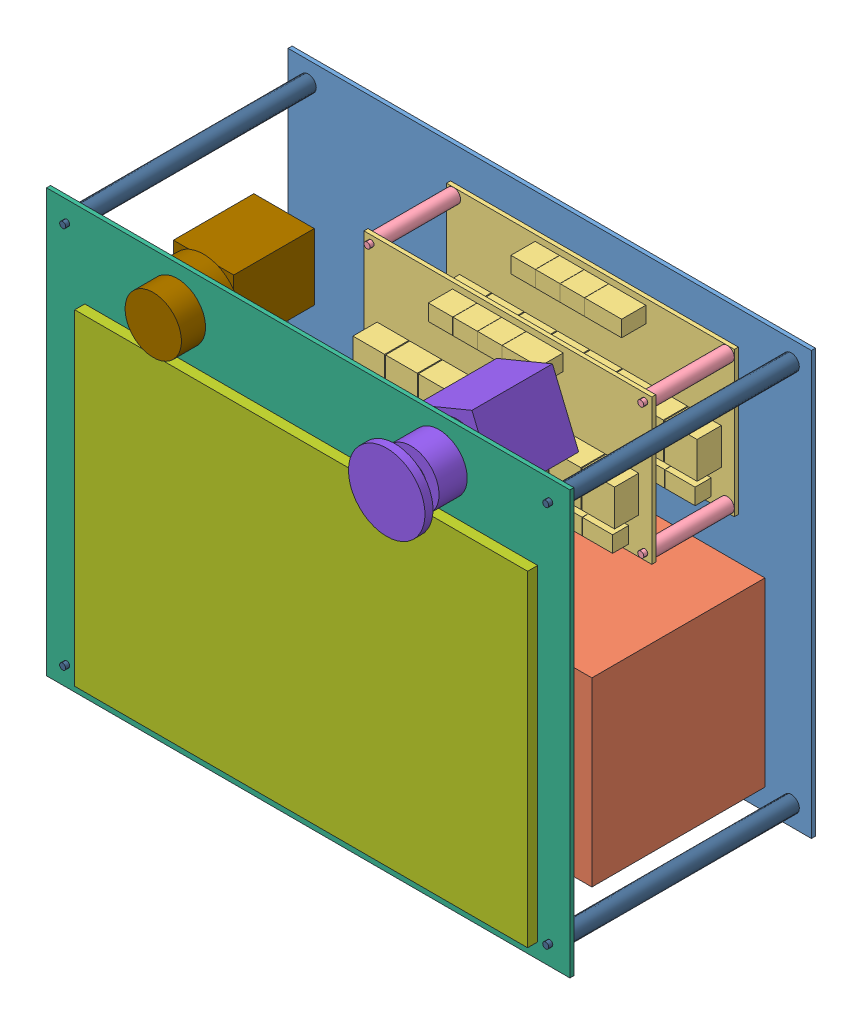
SolidWorks assembly 总装配, configuration 默认. Lengths in mm.
Overall size (260 214.3 150).
19 component instances, 11 part files, 26 mates.
Components (placement in the parent):
- 下板-1: 下板 [默认] at (-128.3079 -118.1194 249) size (260 210 2)
- PLC（32点）-1: PLC（32点） [默认] at (-41.3893 -17.5339 251) x (1 0 0) z (0 -1 0) size (150 86 90)
- 双层继电器-1: 双层继电器 [默认] at (22.8373 30.4222 115) size (143 72 57)
  - 继电器-1: 继电器 [默认] at (-70.4427 -27.2396 136) size (143 72 14)
  - 铜柱-1: 铜柱 [默认] at (-66.9427 -23.7396 138) size (7 7 47)
  - 铜柱-2: 铜柱 [默认] at (69.0573 41.2604 138) size (7 7 47)
  - 铜柱-3: 铜柱 [默认] at (-66.9427 41.2604 138) size (7 7 47)
  - 铜柱-4: 铜柱 [默认] at (69.0573 -23.7396 138) size (7 7 47)
  - 继电器-2: 继电器 [默认] at (-70.4427 -27.2396 177) size (143 72 14)
- 报警器-1: 报警器 [默认] at (-85.4665 -71.2384 251) size (55 69.37 56)
- 上板-1: 上板 [默认] at (-128.3079 -118.1194 369) size (260 210 2)
- 触摸屏-1: 触摸屏 [默认] at (-109.3079 -110.6091 371) size (225 162 34)
- 急停按钮-3: 急停按钮 [默认] at (66.6921 71.3517 397) x (-0.923728 -0.383049 0) z (0 0 -1) size (38 38 75)
- 启动按钮-2: 启动按钮 [默认] at (-63.3079 71.3517 371) size (36 36 65)
- 长铜柱-1: 长铜柱 [默认] at (-118.3079 81.8806 251) size (8 8 126)
- 长铜柱-2: 长铜柱 [默认] at (121.6921 81.8806 251) size (8 8 126)
- 长铜柱-3: 长铜柱 [默认] at (121.6921 -108.1194 251) x (0.995644 0.093241 0) z (0 0 1) size (8 8 126)
- 长铜柱-4: 长铜柱 [默认] at (-118.3079 -108.1194 251) size (8 8 126)
- 触摸屏插头-1: 触摸屏插头 [默认] at (-79.0276 -41.5679 352) size (14 33 47)
Mates (geometry in assembly coordinates):
- 平行1: parallel anti-aligned: plane of 下板-1 through (-128.3079 -118.1194 251) normal (0 0 1); plane of PLC（32点）-1 through (-41.3893 -107.5339 251) normal (0 0 -1)
- 重合1: coincident anti-aligned: plane of 下板-1 through (-128.3079 -118.1194 251) normal (0 0 1); plane of PLC（32点）-1 through (-41.3893 -107.5339 251) normal (0 0 -1)
- 重合2: coincident anti-aligned: plane of 下板-1 through (-128.3079 -118.1194 251) normal (0 0 1); plane of 双层继电器-1/继电器-1 through (-47.6054 3.1827 251) normal (0 0 -1)
- 重合3: coincident anti-aligned: plane of 下板-1 through (-128.3079 -118.1194 251) normal (0 0 1); plane of 报警器-1 through (-85.4665 -71.2384 251) normal (0 0 -1)
- 重合12: coincident anti-aligned: plane of 上板-1 through (-128.3079 -118.1194 371) normal (0 0 1); plane of 触摸屏-1 through (-109.3079 -110.6091 371) normal (0 0 -1)
- 重合14: coincident anti-aligned: plane of 上板-1 through (-128.3079 -118.1194 371) normal (0 0 1); plane of 急停按钮-3 through (66.6921 71.3517 371) normal (0 0 -1)
- 重合15: coincident anti-aligned: plane of 上板-1 through (-128.3079 -118.1194 371) normal (0 0 1); plane of 启动按钮-2 through (-63.3079 71.3517 371) normal (0 0 -1)
- 重合16: coincident anti-aligned: plane of 上板-1 through (-128.3079 -118.1194 371) normal (0 0 1); plane of 触摸屏-1 through (-109.3079 -110.6091 371) normal (0 0 -1)
- 重合17: coincident anti-aligned: plane of 上板-1 through (109.1921 45.3909 369) normal (-1 0 0); plane of 触摸屏-1 through (109.1921 -104.6091 352) normal (1 0 0)
- 重合18: coincident anti-aligned: plane of 上板-1 through (-105.8079 45.3909 369) normal (0 -1 0); plane of 触摸屏-1 through (109.1921 45.3909 352) normal (0 1 0)
- 重合20: coincident anti-aligned: plane of 上板-1 through (-128.3079 -118.1194 369) normal (0 0 -1); plane of 长铜柱-1 through (-118.3079 81.8806 369) normal (0 0 1)
- 重合21: coincident anti-aligned: plane of 上板-1 through (-128.3079 -118.1194 369) normal (0 0 -1); plane of 长铜柱-2 through (121.6921 81.8806 369) normal (0 0 1)
- 重合24: coincident anti-aligned: plane of 上板-1 through (-128.3079 -118.1194 369) normal (0 0 -1); plane of 长铜柱-4 through (-118.3079 -108.1194 369) normal (0 0 1)
- 同心9: concentric aligned: circle of 上板-1; circle of 长铜柱-4
- 重合26: coincident anti-aligned: plane of 上板-1 through (-128.3079 -118.1194 369) normal (0 0 -1); plane of 长铜柱-3 through (121.6921 -108.1194 369) normal (0 0 1)
- 同心10: concentric aligned: circle of 上板-1; circle of 长铜柱-3
- 重合27: coincident anti-aligned: plane of 下板-1 through (-128.3079 -118.1194 251) normal (0 0 1); plane of 长铜柱-1 through (-118.3079 81.8806 251) normal (0 0 -1)
- 同心11: concentric aligned: circle of 下板-1; circle of 长铜柱-1
- 重合28: coincident anti-aligned: plane of 触摸屏-1 through (-109.3079 -110.6091 352) normal (0 0 -1); plane of 触摸屏插头-1 through (-79.0276 -41.5679 352) normal (0 0 1)
- 同心12: concentric aligned: circle of 触摸屏-1; circle of 触摸屏插头-1
- 同心13: concentric anti-aligned: circle of 触摸屏-1; circle of 触摸屏插头-1
- 同心14: concentric aligned: cylinder of 上板-1 through (66.6921 71.3517 369) axis (0 0 1) radius 11; cylinder of 急停按钮-3 through (66.6921 71.3517 369) axis (0 0 1) radius 11
- 同心16: concentric aligned: cylinder of 上板-1 through (-63.3079 71.3517 369) axis (0 0 1) radius 11; cylinder of 启动按钮-2 through (-63.3079 71.3517 368) axis (0 0 1) radius 11
- 重合31: coincident anti-aligned: cylinder of 下板-1 through (121.6921 -108.1194 249) axis (0 0 1) radius 1.5; circle of 长铜柱-3
- 同心17: concentric aligned: cylinder of 下板-1 through (121.6921 81.8806 249) axis (0 0 1) radius 1.5; cylinder of 长铜柱-2 through (121.6921 81.8806 247) axis (0 0 1) radius 1.5
- 同心18: concentric anti-aligned: cylinder of 上板-1 through (121.6921 81.8806 361) axis (0 0 1) radius 1.5; cylinder of 长铜柱-2 through (121.6921 81.8806 373) axis (0 0 -1) radius 1.5
